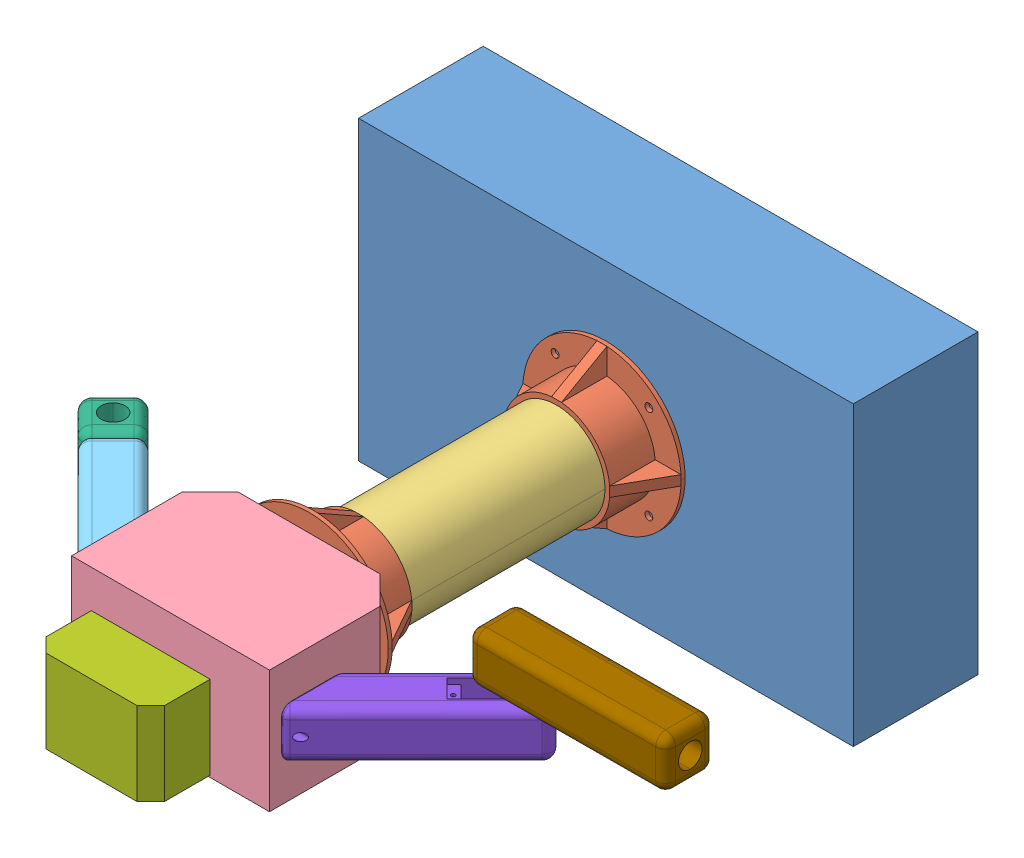
SolidWorks assembly Robo, configuration Default. Lengths in mm.
Overall size (329.07 162.5 323).
12 component instances, 10 part files, 0 mates.
Components (placement in the parent):
- Robo.igs-1: Robo.igs [Default] at origin size (329.07 162.5 323)
  - Part1.igs-1: Part1.igs [Default] at (0 0 78.1618) size (250 150 63)
  - Part3.igs-1: Part3.igs [Default] at (0 0 78.1618) size (84.65 84.35 25)
  - Part3.igs-2: Part3.igs [Default] at (0 0 234.1618) x (-1 0 0) z (0 0 -1) size (84.65 84.35 25)
  - Part2.igs-1: Part2.igs [Default] at (0 0 78.1618) size (51.76 51.43 150)
  - Part4.igs-1: Part4.igs [Default] at (31.7642 74.7696 0) size (100 62 70)
  - Part1.1.igs-1: Part1.1.igs [Default] at (-76.5165 0 253.6453) x (-0.707107 0 -0.707107) z (0 -1 0) size (99.69 27.86 46.28)
  - right lower arm.igs-1: right lower arm.igs [Default] at (-120.7107 -37.5 209.4511) x (0 -1 0) z (-0.707107 0 0.707107) size (100 25 25)
  - Part5.igs-1: Part5.igs [Default] at (49.1523 74.7696 0) size (60 42 30)
  - Part1.1.1.igs-1: Part1.1.1.igs [Default] at (76.5165 0 253.6453) x (0.707107 0 -0.707107) z (0 1 0) size (99.69 27.86 46.28)
  - right lower arm.1.igs-1: right lower arm.1.igs [Default] at (140.6285 28 229.3695) x (0.999992 0 -0.004086) z (-0.004086 0 -0.999992) size (100 25 25)
  - Part10.igs-1: Part10.igs [Default] at (0 0 298.1618) size (18 18 16)
